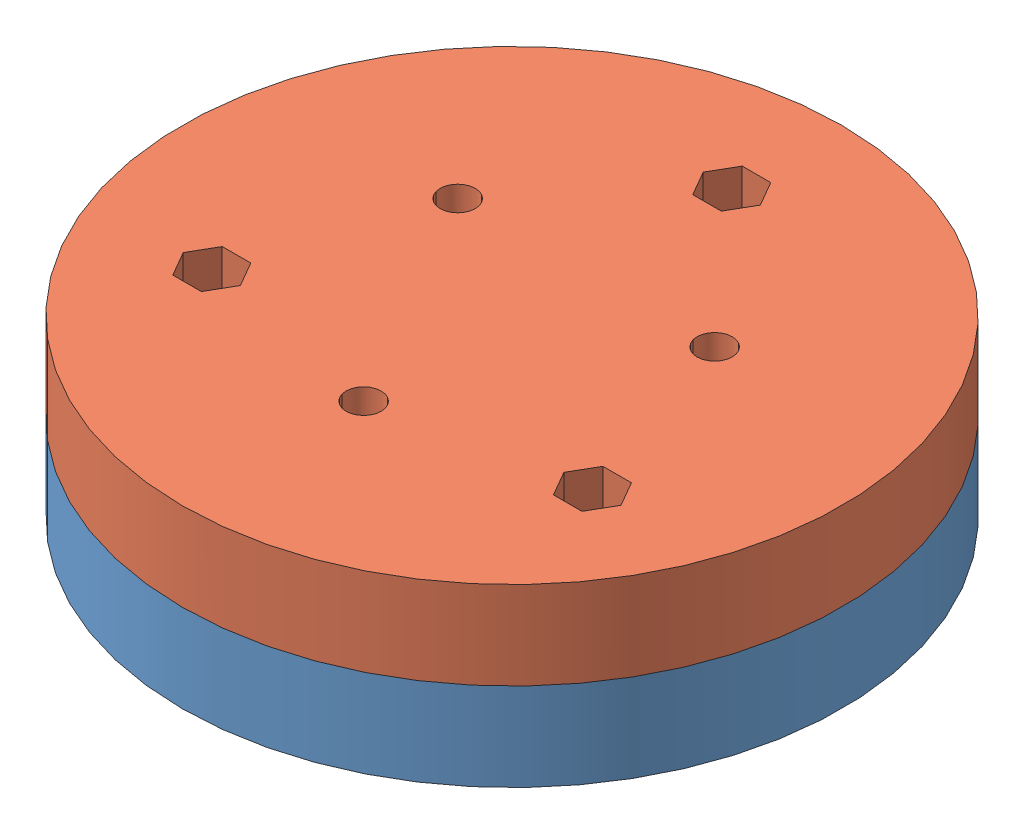
SolidWorks assembly 转换口, configuration 默认. Lengths in mm.
Overall size (81.96 16 81.96).
2 component instances, 2 part files, 3 mates.
Components (placement in the parent):
- 转换口卷筒一侧-1: 转换口卷筒一侧 [默认] at (1.8035 -2.4069 60) size (60 8 60)
- 转换口电机一侧-1: 转换口电机一侧 [默认] at (1.8035 13.5931 60) x (-0.5 0 -0.866025) z (-0.866025 0 0.5) size (60 8 60)
Mates (geometry in assembly coordinates):
- 同心1: concentric anti-aligned: cylinder of 转换口底座一侧-1 through (1.8035 5.5931 60) axis (0 -1 0) radius 30; cylinder of 转换口电机一侧-1 through (1.8035 5.5931 60) axis (0 1 0) radius 30
- 同心2: concentric anti-aligned: circle of 转换口卷筒一侧-1; circle of 转换口电机一侧-1
- 重合3: coincident anti-aligned: plane of 转换口底座一侧-1 through (1.8035 5.5931 60) normal (0 1 0); plane of 转换口电机一侧-1 through (1.8035 5.5931 60) normal (0 -1 0)
